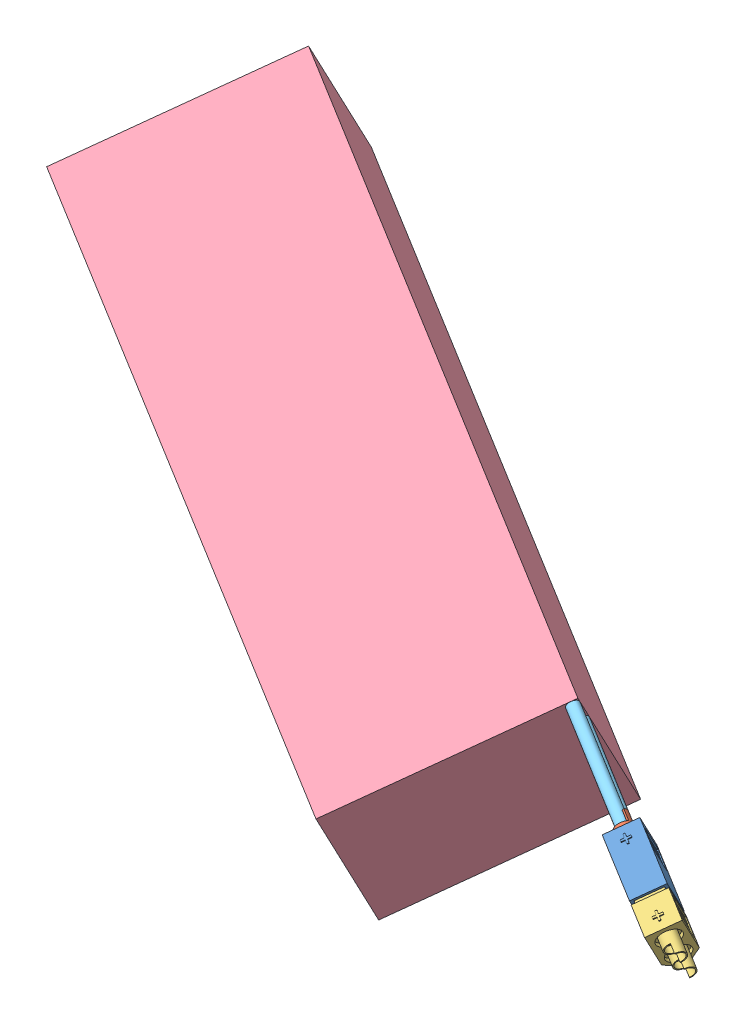
SolidWorks assembly Black Magic Li-Po 22(сборка), configuration По умолчанию. Lengths in mm.
Overall size (225.81 120.91 128.61).
6 component instances, 5 part files, 17 mates.
Components (placement in the parent):
- XT-60_Macho-2: XT-60_Macho [Valor predeterminado] at (613.6046 -99.3453 76.714) x (-0.141182 -0.846515 -0.513302) z (0.847928 -0.371013 0.378638) size (16.3 8.2 16.2)
- PinoXT-60_Macho-1: PinoXT-60_Macho [Valor predeterminado] at (609.8575 -105.5328 65.8371) x (0.471348 0.854521 -0.218232) z (0.242587 -0.363516 -0.899449) size (4.3 26.83 4.3)
- PinoXT-60_Macho-2: PinoXT-60_Macho [Valor predeterminado] at (610.8599 -99.5226 69.4816) x (-0.476001 -0.84725 0.235777) z (-0.233324 0.380154 0.89501) size (4.3 26.83 4.3)
- XT-60_Macho 1-1: XT-60_Macho 1 [Valor predeterminado] at (639.1623 -105.5641 79.9403) x (-0.141182 -0.846515 -0.513302) z (-0.847928 0.371013 -0.378638) size (16.3 8.2 21.5)
- Black Magic Li-Po 22.2V-1: Black Magic Li-Po 22.2V [По умолчанию] at (506.5799 -68.8012 50.5189) x (-0.847928 0.371013 -0.378638) z (-0.141182 -0.846515 -0.513302) size (160 57 47)
- Провода-2: Провода [По умолчанию] at (586.9634 -95.5155 55.6139) x (-0.847928 0.371013 -0.378638) z (-0.141182 -0.846515 -0.513302) size (30 3.1 10.2)
Mates (geometry in assembly coordinates):
- Совпадение8: coincident: plane of Black Magic Li-Po 22.2V-1; plane of ? through (-3.6 1125.3897 -95.7322) normal (0 0.090078 -0.995935)
- Заблокировать2: lock: unknown of Black Magic Li-Po 22.2V-1; unknown of ?
- Заблокировать3: lock: unknown of Black Magic Li-Po 22.2V-1; unknown of ?
- Concêntrico1: concentric aligned: cylinder of XT-60_Macho-2 through (627.8336 -113.3983 73.8642) axis (-0.847928 0.371013 -0.378638) radius 2.15; cylinder of PinoXT-60_Macho-1 through (618.3368 -109.2429 69.6235) axis (-0.847928 0.371013 -0.378638) radius 2.15
- Concêntrico2: concentric aligned: cylinder of XT-60_Macho-2 through (628.836 -107.388 77.5087) axis (-0.847928 0.371013 -0.378638) radius 2.15; cylinder of PinoXT-60_Macho-2 through (619.3392 -103.2327 73.2679) axis (-0.847928 0.371013 -0.378638) radius 2.15
- Distância1: distance = 1.4 mm aligned: plane of PinoXT-60_Macho-1 through (627.6599 -111.0417 72.8649) normal (0.847928 -0.371013 0.378638); plane of XT-60_Macho-2 through (627.3411 -105.3557 82.8479) normal (0.847928 -0.371013 0.378638)
- Distância2: distance = 1.4 mm aligned: plane of PinoXT-60_Macho-2 through (626.6255 -108.6902 77.4855) normal (0.847928 -0.371013 0.378638); plane of XT-60_Macho-2 through (627.3411 -105.3557 82.8479) normal (0.847928 -0.371013 0.378638)
- LimitDistance1: limit distance = 1 mm anti-aligned: plane of XT-60_Macho 1-1 through (633.2986 -101.9088 75.5249) normal (-0.847928 0.371013 -0.378638); plane of XT-60_Macho-2 through (627.3411 -105.3557 82.8479) normal (0.847928 -0.371013 0.378638)
- Width1: width: plane of XT-60_Macho-2 through (618.7595 -113.4031 69.3545) normal (0.141182 0.846515 0.513302); plane of XT-60_Macho-2 through (623.0713 -99.6587 73.166) normal (-0.141182 -0.846515 -0.513302); plane of XT-60_Macho 1-1 through (633.8268 -108.4358 84.5852) normal (0.141182 0.846515 0.513302); plane of XT-60_Macho 1-1 through (634.1062 -118.6755 73.9259) normal (-0.141182 -0.846515 -0.513302)
- Width2: width: plane of XT-60_Macho 1-1 through (637.1991 -105.9161 79.5021) normal (0.510965 0.381787 -0.770165); plane of XT-60_Macho 1-1 through (632.1758 -118.3349 78.5827) normal (-0.510965 -0.381787 0.770165); plane of XT-60_Macho-2 through (619.6479 -102.2167 78.3261) normal (0.510965 0.381787 -0.770165); plane of XT-60_Macho-2 through (621.4106 -109.6163 67.128) normal (-0.510965 -0.381787 0.770165)
- Концентричный1: concentric aligned: circle of PinoXT-60_Macho-1; circle of Провода-2
- Концентричный2: concentric aligned: circle of PinoXT-60_Macho-2; circle of Провода-2
- Совпадение11: coincident anti-aligned: plane of PinoXT-60_Macho-2 through (613.4037 -100.6356 70.6175) normal (-0.847928 0.371013 -0.378638); plane of Провода-2 through (613.4037 -100.6356 70.6175) normal (0.847928 -0.371013 0.378638)
- Совпадение12: coincident anti-aligned: plane of Black Magic Li-Po 22.2V-1 through (553.2161 -149.1494 78.6344) normal (0.847928 -0.371013 0.378638); plane of Провода-2 through (587.9658 -89.5052 59.2583) normal (-0.847928 0.371013 -0.378638)
- Касательность1: tangent aligned: plane of Black Magic Li-Po 22.2V-1 through (582.3411 -127.3876 34.735) normal (0.510965 0.381787 -0.770165); cylinder of Провода-2 through (586.9634 -95.5155 55.6139) axis (0.847928 -0.371013 0.378638) radius 1.55
- Касательность2: tangent aligned: plane of Black Magic Li-Po 22.2V-1 through (506.5799 -68.8012 50.5189) normal (0.141182 0.846515 0.513302); cylinder of Провода-2 through (587.9658 -89.5052 59.2583) axis (0.847928 -0.371013 0.378638) radius 1.55
- Касательность3: tangent aligned: plane of Black Magic Li-Po 22.2V-1 through (582.3411 -127.3876 34.735) normal (0.510965 0.381787 -0.770165); cylinder of Провода-2 through (587.9658 -89.5052 59.2583) axis (0.847928 -0.371013 0.378638) radius 1.55
